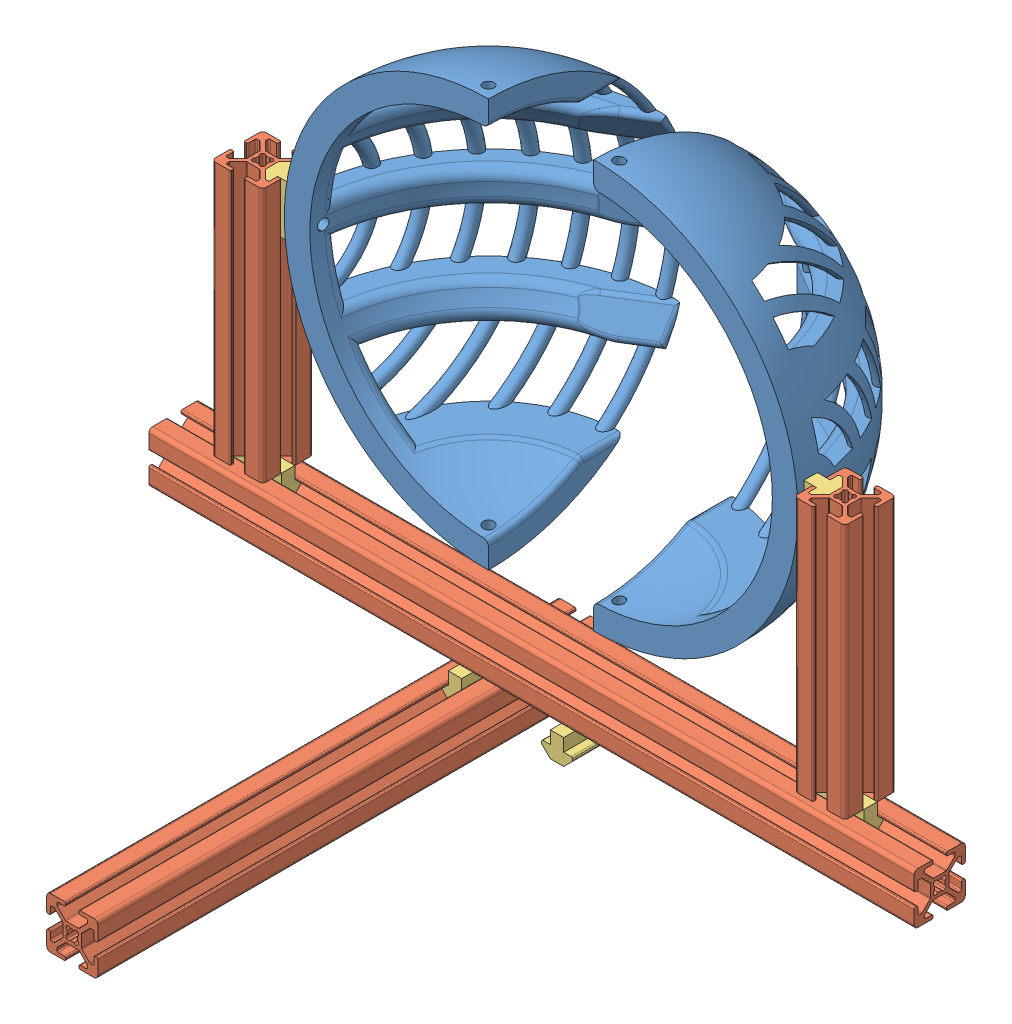
SolidWorks assembly Collector_Assembly, configuration Default. Lengths in mm.
Overall size (300 220.52 195.01).
15 component instances, 3 part files, 41 mates.
Components (placement in the parent):
- Collector Hand-1: Collector Hand [Default] at (43.9345 -53.2163 -71.1291) size (80.24 160 80)
- Collector Hand-2: Collector Hand [Default] at (2.6754 106.7837 -71.1291) x (-1 0 0) z (0 0 1) size (80.24 160 80)
- 2020_aluminum_bar-1: 2020_aluminum_bar [20-2020-300mm] at (-125.4411 -76.722 -76.1244) x (0 0 -1) z (1 0 0) size (20 20 300)
- 2020_aluminum_bar_side_connector-1: 2020_aluminum_bar_side_connector [Default] at (-80.8303 -73.0635 -76.1268) x (0 -1 0) z (0 0 -1) size (9.85 20 11.99)
- 2020_aluminum_bar-2: 2020_aluminum_bar [20-2020-100mm] at (-90.8303 -63.2163 -76.1268) x (0 0 1) z (0 1 0) size (20 20 100)
- 2020_aluminum_bar_side_connector-2: 2020_aluminum_bar_side_connector [Default] at (-87.1717 36.7837 -76.1291) x (-1 0 0) z (0 0 1) size (9.85 20 11.99)
- 2020_aluminum_bar_side_connector-3: 2020_aluminum_bar_side_connector [Default] at (147.4402 -73.0635 -76.1268) x (0 -1 0) z (0 0 -1) size (9.85 20 11.99)
- 2020_aluminum_bar-3: 2020_aluminum_bar [20-2020-100mm] at (137.4402 36.7837 -76.1268) x (-1 0 0) z (0 -1 0) size (20 20 100)
- 2020_aluminum_bar_side_connector-4: 2020_aluminum_bar_side_connector [Default] at (133.7816 16.7837 -76.1291) size (9.85 20 11.99)
- 2020_aluminum_bar-4: 2020_aluminum_bar [ 20-2020-160mm] at (-5.4411 -103.7334 -116.1268) size (20 20 160)
- 2020_aluminum_bar_side_connector-5: 2020_aluminum_bar_side_connector [Default] at (4.5613 -80.3806 -76.1268) x (0 1 0) z (0 0 1) size (9.85 20 11.99)
- 2020_aluminum_bar_side_connector-6: 2020_aluminum_bar_side_connector [Default] at (-5.4387 -100.0748 -86.1268) x (0 -1 0) z (-1 0 0) size (9.85 20 11.99)
- 2020_aluminum_bar-5: 2020_aluminum_bar [ 20-2020-160mm] at (34.5589 -103.7334 -116.1221) size (20 20 160)
- 2020_aluminum_bar_side_connector-7: 2020_aluminum_bar_side_connector [Default] at (44.5613 -80.3806 -76.1221) x (0 1 0) z (0 0 1) size (9.85 20 11.99)
- 2020_aluminum_bar_side_connector-8: 2020_aluminum_bar_side_connector [Default] at (34.5613 -100.0748 -86.1221) x (0 -1 0) z (-1 0 0) size (9.85 20 11.99)
Mates (geometry in assembly coordinates):
- Parallel1: parallel aligned: plane of Collector Hand-1 through (43.9345 26.7837 -71.1291) normal (0 0 1); plane of Collector Hand-2 through (2.6754 26.7837 -71.1291) normal (0 0 1)
- Parallel3: parallel anti-aligned: plane of Collector Hand-1 through (123.9345 66.7837 -151.1291) normal (0 1 0); plane of Collector Hand-2 through (-77.3246 -13.2163 -151.1291) normal (0 -1 0)
- Parallel4: parallel anti-aligned: plane of Collector Hand-1 through (43.9345 26.7837 -71.1291) normal (-1 0 0); plane of Collector Hand-2 through (2.6754 26.7837 -71.1291) normal (1 0 0)
- Coincident1: coincident anti-aligned: plane of 2020_aluminum_bar-1 through (174.5589 -73.0635 -78.5129) normal (0 1 0); plane of 2020_aluminum_bar_side_connector-1 through (-100.8303 -73.0635 -73.7368) normal (0 -1 0)
- Coincident2: coincident anti-aligned: plane of 2020_aluminum_bar-1 through (174.5589 -72.9147 -73.3768) normal (0 0.707107 -0.707107); plane of 2020_aluminum_bar_side_connector-1 through (-100.8303 -69.817 -70.279) normal (0 -0.707107 0.707107)
- Concentric1: concentric anti-aligned: cylinder of 2020_aluminum_bar_side_connector-1 through (-90.8303 -69.2163 -76.1268) axis (0 1 0) radius 2.1; cylinder of 2020_aluminum_bar-2 through (-90.8303 36.7837 -76.1268) axis (0 -1 0) radius 2.0955
- Parallel5: parallel aligned: plane of 2020_aluminum_bar-1 through (174.5589 -73.5851 -66.1244) normal (0 0 1); plane of 2020_aluminum_bar-2 through (-82.3289 36.7837 -66.1268) normal (0 0 1)
- Coincident5: coincident anti-aligned: plane of 2020_aluminum_bar_side_connector-1 through (-100.8303 -63.2163 -78.7568) normal (0 1 0); plane of 2020_aluminum_bar-2 through (-87.6934 -63.2163 -67.1174) normal (0 -1 0)
- Coincident6: coincident anti-aligned: plane of 2020_aluminum_bar-2 through (-87.1717 36.7837 -73.7383) normal (1 0 0); plane of 2020_aluminum_bar_side_connector-2 through (-87.1717 16.7837 -78.5191) normal (-1 0 0)
- Coincident7: coincident anti-aligned: plane of 2020_aluminum_bar-2 through (-83.925 36.7837 -70.2812) normal (0.707107 0 -0.707107); plane of 2020_aluminum_bar_side_connector-2 through (-83.9252 16.7837 -70.2814) normal (-0.707107 0 0.707107)
- Tangent1: tangent anti-aligned: sphere of Collector Hand-2; plane of 2020_aluminum_bar_side_connector-2 through (-77.3246 16.7837 -73.4991) normal (1 0 0)
- Concentric3: concentric anti-aligned: cylinder of Collector Hand-2 through (2.6754 26.7837 -76.1291) axis (-1 0 0) radius 2.1; cylinder of 2020_aluminum_bar_side_connector-2 through (-83.3246 26.7837 -76.1291) axis (1 0 0) radius 2.1
- Coincident8: coincident aligned: plane of 2020_aluminum_bar-2 through (-87.6934 36.7837 -67.1174) normal (0 1 0); plane of 2020_aluminum_bar_side_connector-2 through (-82.8346 36.7837 -81.6163) normal (0 1 0)
- Parallel6: parallel aligned: plane of Collector Hand-2 through (2.6754 26.7837 -71.1291) normal (0 0 1); plane of 2020_aluminum_bar-2 through (-82.3289 36.7837 -66.1268) normal (0 0 1)
- Coincident11: coincident anti-aligned: plane of 2020_aluminum_bar-1 through (174.5589 -73.0635 -78.5129) normal (0 1 0); plane of 2020_aluminum_bar_side_connector-3 through (127.4402 -73.0635 -73.7368) normal (0 -1 0)
- Coincident12: coincident anti-aligned: plane of 2020_aluminum_bar-1 through (174.5589 -72.9147 -73.3768) normal (0 0.707107 -0.707107); plane of 2020_aluminum_bar_side_connector-3 through (127.4402 -69.817 -70.279) normal (0 -0.707107 0.707107)
- Concentric4: concentric aligned: cylinder of 2020_aluminum_bar_side_connector-3 through (137.4402 -69.2163 -76.1268) axis (0 1 0) radius 2.1; cylinder of 2020_aluminum_bar-3 through (137.4402 -63.2163 -76.1268) axis (0 1 0) radius 2.0955
- Parallel7: parallel aligned: plane of 2020_aluminum_bar-1 through (174.5589 -73.5851 -66.1244) normal (0 0 1); plane of 2020_aluminum_bar-3 through (140.5771 -63.2163 -66.1268) normal (0 0 1)
- Coincident14: coincident anti-aligned: plane of 2020_aluminum_bar_side_connector-3 through (127.4402 -63.2163 -78.7568) normal (0 1 0); plane of 2020_aluminum_bar-3 through (128.4308 -63.2163 -79.2637) normal (0 -1 0)
- Coincident15: coincident anti-aligned: plane of 2020_aluminum_bar-3 through (133.7816 -63.2163 -73.7383) normal (-1 0 0); plane of 2020_aluminum_bar_side_connector-4 through (133.7816 36.7837 -78.5191) normal (1 0 0)
- Coincident16: coincident anti-aligned: plane of 2020_aluminum_bar-3 through (130.5349 -63.2163 -70.2812) normal (-0.707107 0 -0.707107); plane of 2020_aluminum_bar_side_connector-4 through (130.5351 36.7837 -70.2814) normal (0.707107 0 0.707107)
- Coincident17: coincident aligned: plane of 2020_aluminum_bar-3 through (128.4308 36.7837 -79.2637) normal (0 1 0); plane of 2020_aluminum_bar_side_connector-4 through (129.4445 36.7837 -81.6163) normal (0 1 0)
- Tangent3: tangent anti-aligned: sphere of Collector Hand-1; plane of 2020_aluminum_bar_side_connector-4 through (123.9345 36.7837 -73.4991) normal (-1 0 0)
- Concentric7: concentric anti-aligned: cylinder of Collector Hand-1 through (43.9345 26.7837 -76.1291) axis (1 0 0) radius 2.1; cylinder of 2020_aluminum_bar_side_connector-4 through (129.9345 26.7837 -76.1291) axis (-1 0 0) radius 2.1
- Parallel9: parallel aligned: plane of Collector Hand-1 through (43.9345 26.7837 -71.1291) normal (0 0 1); plane of 2020_aluminum_bar-3 through (128.9388 -63.2163 -66.1268) normal (0 0 1)
- Coincident18: coincident anti-aligned: plane of 2020_aluminum_bar-1 through (174.5589 -80.3806 -73.736) normal (0 -1 0); plane of 2020_aluminum_bar_side_connector-5 through (-15.4387 -80.3806 -78.5168) normal (0 1 0)
- Coincident19: coincident anti-aligned: plane of 2020_aluminum_bar-1 through (174.5589 -83.6273 -70.2788) normal (0 -0.707107 -0.707107); plane of 2020_aluminum_bar_side_connector-5 through (-15.4387 -83.6271 -70.279) normal (0 0.707107 0.707107)
- Coincident20: coincident anti-aligned: plane of 2020_aluminum_bar-4 through (-3.0526 -100.0748 43.8732) normal (0 1 0); plane of 2020_aluminum_bar_side_connector-6 through (-3.0487 -100.0748 -66.1268) normal (0 -1 0)
- Coincident21: coincident anti-aligned: plane of 2020_aluminum_bar-4 through (-8.1888 -99.9261 43.8732) normal (0.707107 0.707107 0); plane of 2020_aluminum_bar_side_connector-6 through (-11.2865 -96.8283 -66.1268) normal (-0.707107 -0.707107 0)
- Concentric8: concentric anti-aligned: cylinder of 2020_aluminum_bar_side_connector-5 through (-5.4387 -84.2277 -76.1268) axis (0 -1 0) radius 2.1; cylinder of 2020_aluminum_bar_side_connector-6 through (-5.4387 -96.2277 -76.1268) axis (0 1 0) radius 2.1
- Distance1: distance = 30 mm aligned: plane of 2020_aluminum_bar_side_connector-6 through (0.0484 -95.7377 -86.1268) normal (0 0 -1); plane of 2020_aluminum_bar-4 through (3.5683 -100.5965 -116.1268) normal (0 0 -1)
- Coincident23: coincident anti-aligned: plane of 2020_aluminum_bar_side_connector-5 through (-15.4387 -90.2277 -73.4968) normal (0 -1 0); plane of 2020_aluminum_bar_side_connector-6 through (-8.0687 -90.2277 -66.1268) normal (0 1 0)
- Coincident24: coincident anti-aligned: plane of 2020_aluminum_bar-1 through (174.5589 -80.3806 -73.736) normal (0 -1 0); plane of 2020_aluminum_bar_side_connector-7 through (24.5613 -80.3806 -78.5121) normal (0 1 0)
- Coincident25: coincident anti-aligned: plane of 2020_aluminum_bar-1 through (174.5589 -80.5294 -78.8721) normal (0 -0.707107 0.707107); plane of 2020_aluminum_bar_side_connector-7 through (24.5613 -83.6271 -81.9698) normal (0 0.707107 -0.707107)
- Coincident26: coincident anti-aligned: plane of 2020_aluminum_bar-5 through (36.9474 -100.0748 43.8779) normal (0 1 0); plane of 2020_aluminum_bar_side_connector-8 through (36.9513 -100.0748 -66.1221) normal (0 -1 0)
- Coincident27: coincident anti-aligned: plane of 2020_aluminum_bar-5 through (31.8112 -99.9261 43.8779) normal (0.707107 0.707107 0); plane of 2020_aluminum_bar_side_connector-8 through (28.7135 -96.8283 -66.1221) normal (-0.707107 -0.707107 0)
- Distance2: distance = 30 mm aligned: plane of 2020_aluminum_bar_side_connector-8 through (40.0484 -95.7377 -86.1221) normal (0 0 -1); plane of 2020_aluminum_bar-5 through (43.5683 -100.5965 -116.1221) normal (0 0 -1)
- Concentric9: concentric anti-aligned: cylinder of 2020_aluminum_bar_side_connector-7 through (34.5613 -84.2277 -76.1221) axis (0 -1 0) radius 2.1; cylinder of 2020_aluminum_bar_side_connector-8 through (34.5613 -96.2277 -76.1221) axis (0 1 0) radius 2.1
- Coincident29: coincident anti-aligned: plane of 2020_aluminum_bar_side_connector-7 through (24.5613 -90.2277 -73.4921) normal (0 -1 0); plane of 2020_aluminum_bar_side_connector-8 through (31.9313 -90.2277 -66.1221) normal (0 1 0)
- Distance3: distance = 130 mm aligned: plane of 2020_aluminum_bar-5 through (44.5589 -106.8703 43.8779) normal (1 0 0); plane of 2020_aluminum_bar-1 through (174.5589 -73.5851 -85.1338) normal (1 0 0)
- Distance4: distance = 110 mm aligned: plane of 2020_aluminum_bar-4 through (-15.4411 -112.2348 43.8732) normal (-1 0 0); plane of 2020_aluminum_bar-1 through (-125.4411 -73.5851 -85.1338) normal (-1 0 0)
